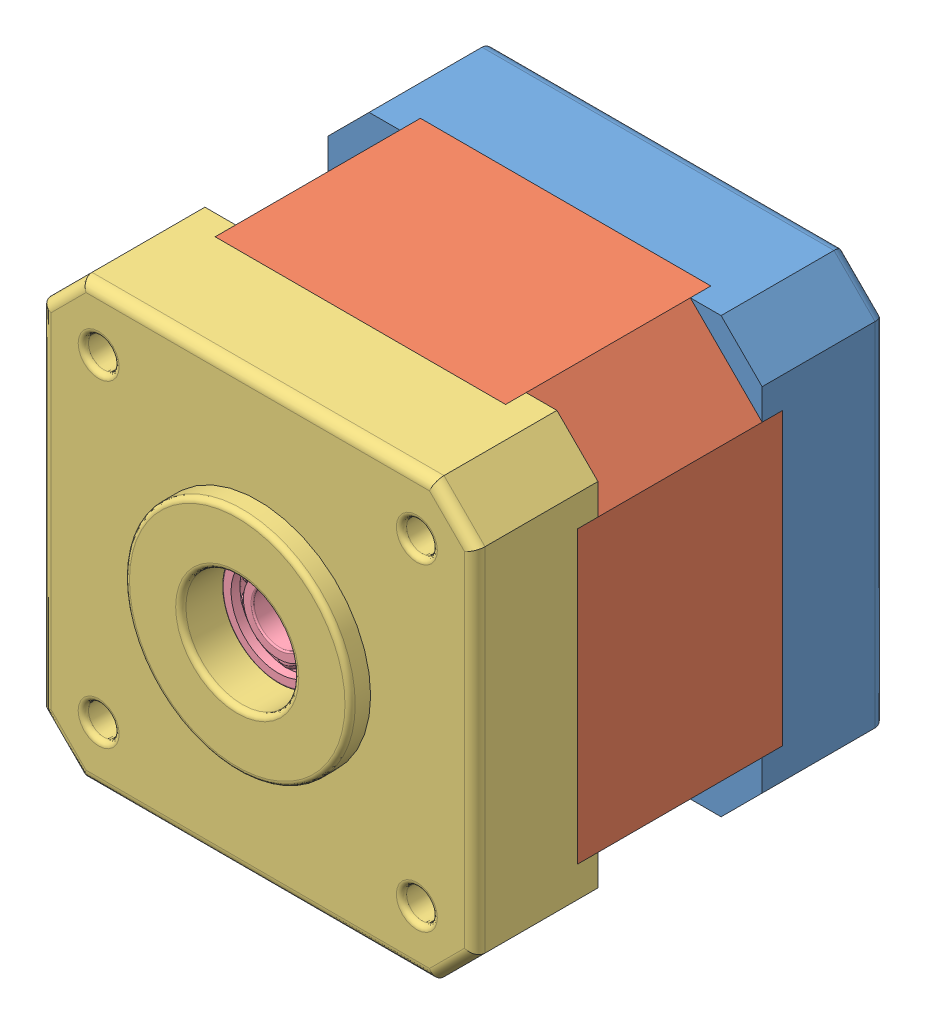
SolidWorks assembly Assieme, configuration Default. Lengths in mm.
Overall size (42.3 42.3 42).
9 component instances, 5 part files, 16 mates.
Components (placement in the parent):
- Base-1: Base [Default] at (-6.1494 -1.1094 36.3) size (42.3 42.3 12)
- Corpo-1: Corpo [Default] at (-6.1494 -1.1094 46.3) size (42.3 42.3 20)
- Piastra posteriore-1: Piastra posteriore [Default] at (-6.1494 -1.1094 76.3) x (-1 0 0) z (0 0 -1) size (42.3 42.3 14)
- instrument ball bearing_68_am-5: instrument ball bearing_68_am [AFBMA 12.1.4.1 - 0050-11 - 10,DE,AC,10_68] at (-6.1494 -1.1094 39.8) x (0 0 -1) z (0.544131 0.839 0) size (3 11 11)
- instrument ball bearing_68_am-6: instrument ball bearing_68_am [AFBMA 12.1.4.1 - 0050-11 - 10,DE,AC,10_68] at (-6.1494 -1.1094 72.8) x (0 0 -1) z (0.999293 -0.037607 0) size (3 11 11)
- pan head cross recess screw_din-5: pan head cross recess screw_din [DIN EN ISO 7045 - M3 x 5 - Z - 5N] at (-21.6494 14.3906 36.9) x (0 0 1) z (-1 0 0) size (6.65 5.6 5.6)
- pan head cross recess screw_din-6: pan head cross recess screw_din [DIN EN ISO 7045 - M3 x 5 - Z - 5N] at (9.3506 14.3906 36.9) x (0 0 1) z (-1 0 0) size (6.65 5.6 5.6)
- pan head cross recess screw_din-7: pan head cross recess screw_din [DIN EN ISO 7045 - M3 x 5 - Z - 5N] at (9.3506 -16.6094 36.9) x (0 0 1) z (-1 0 0) size (6.65 5.6 5.6)
- pan head cross recess screw_din-8: pan head cross recess screw_din [DIN EN ISO 7045 - M3 x 5 - Z - 5N] at (-21.6494 -16.6094 36.9) x (0 0 1) z (-1 0 0) size (6.65 5.6 5.6)
Mates (geometry in assembly coordinates):
- Coincidente1: coincident aligned: plane of Base-1 through (-23.2994 20.0406 48.3) normal (0 1 0); plane of Corpo-1 through (-20.2994 20.0406 66.3) normal (0 1 0)
- Coincidente2: coincident aligned: plane of Base-1 through (15.0006 -18.2594 48.3) normal (1 0 0); plane of Corpo-1 through (15.0006 -15.2594 66.3) normal (1 0 0)
- Coincidente3: coincident anti-aligned: plane of Base-1 through (-6.1494 -1.1094 46.3) normal (0 0 1); plane of Corpo-1 through (-6.1494 -1.1094 46.3) normal (0 0 -1)
- Coincidente4: coincident aligned: plane of Corpo-1 through (-20.2994 20.0406 66.3) normal (0 1 0); plane of Piastra posteriore-1 through (11.0006 20.0406 64.3) normal (0 1 0)
- Coincidente6: coincident anti-aligned: plane of Corpo-1 through (-6.1494 -1.1094 66.3) normal (0 0 1); plane of Piastra posteriore-1 through (-6.1494 -1.1094 66.3) normal (0 0 -1)
- Coincidente7: coincident aligned: plane of Corpo-1 through (15.0006 -15.2594 66.3) normal (1 0 0); plane of Piastra posteriore-1 through (15.0006 -18.2594 64.3) normal (1 0 0)
- Coincidente9: coincident anti-aligned: plane of Piastra posteriore-1 through (-6.1494 -1.1094 71.3) normal (0 0 1); plane of instrument ball bearing_68_am-6 through (-6.0497 1.5387 71.3) normal (0 0 -1)
- Coincidente10: coincident anti-aligned: plane of Base-1 through (-6.1494 -1.1094 41.3) normal (0 0 -1); plane of instrument ball bearing_68_am-5 through (-9.002 0.7406 41.3) normal (0 0 1)
- Concentrico2: concentric anti-aligned: cylinder of Base-1 through (-21.6494 14.3906 36.3) axis (0 0 1) radius 1.5; cylinder of pan head cross recess screw_din-5 through (-21.6494 14.3906 11.5) axis (0 0 -1) radius 2.8
- Coincidente12: coincident anti-aligned: plane of Base-1 through (-21.6494 14.3906 39.3) normal (0 0 -1); plane of pan head cross recess screw_din-5 through (-21.6494 15.8906 39.3) normal (0 0 1)
- Concentrico3: concentric anti-aligned: cylinder of Base-1 through (9.3506 14.3906 36.3) axis (0 0 1) radius 1.5; cylinder of pan head cross recess screw_din-6 through (9.3506 14.3906 11.5) axis (0 0 -1) radius 2.8
- Coincidente13: coincident anti-aligned: plane of Base-1 through (9.3506 14.3906 39.3) normal (0 0 -1); plane of pan head cross recess screw_din-6 through (9.3506 15.8906 39.3) normal (0 0 1)
- Concentrico4: concentric anti-aligned: cylinder of Base-1 through (9.3506 -16.6094 36.3) axis (0 0 1) radius 1.5; cylinder of pan head cross recess screw_din-7 through (9.3506 -16.6094 11.5) axis (0 0 -1) radius 2.8
- Coincidente14: coincident anti-aligned: plane of Base-1 through (9.3506 -16.6094 39.3) normal (0 0 -1); plane of pan head cross recess screw_din-7 through (9.3506 -15.1094 39.3) normal (0 0 1)
- Concentrico5: concentric anti-aligned: cylinder of Base-1 through (-21.6494 -16.6094 36.3) axis (0 0 1) radius 1.5; cylinder of pan head cross recess screw_din-8 through (-21.6494 -16.6094 11.5) axis (0 0 -1) radius 2.8
- Coincidente15: coincident anti-aligned: plane of Base-1 through (-21.6494 -16.6094 39.3) normal (0 0 -1); plane of pan head cross recess screw_din-8 through (-21.6494 -15.1094 39.3) normal (0 0 1)
